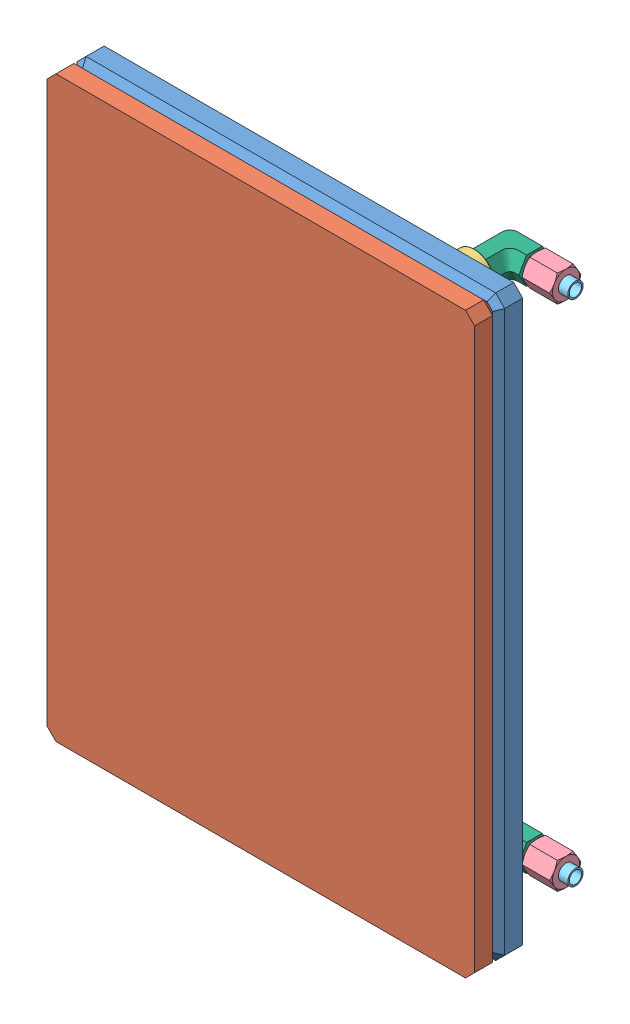
SolidWorks assembly Flanking_Shroud_Assem, configuration Default. Lengths in mm.
Overall size (225.7 304.8 64.93).
14 component instances, 7 part files, 16 mates.
Components (placement in the parent):
- Flanking_Shroud_Outside-1: Flanking_Shroud_Outside [Default] at origin size (225.42 304.8 12.7)
- Flanking_Shroud_Inside-3: Flanking_Shroud_Inside [Default] at (0 0 25.4) x (-1 0 0) z (0 0 -1) size (225.42 304.8 12.7)
- Shroud Plumbing Connection Assem-1: Shroud Plumbing Connection Assem [Default] at (74.7125 134.05 0) x (-1 0 0) z (0 0 1) size (45.23 21.34 39.53)
  - 4452K139_TYPE 316 STAINLESS STL THREADED PIPE FITTING-1: 4452K139_TYPE 316 STAINLESS STL THREADED PIPE FITTING [4452K139] at (0 0 -6.35) x (-1 0 0) z (0 0 -1) size (21.34 21.34 12.7)
  - 50715K324_37 DEGREE FLARED FITTING FOR SS TUBING-1: 50715K324_37 DEGREE FLARED FITTING FOR SS TUBING [50715K324] at (-29.6419 0 -31.226) x (0 0.999967 -0.008151) z (0 -0.008151 -0.999967) size (14.29 16.03 16.5)
  - 50715K316_TYPE 316 SS 37 DEGREE FLARED TUBE FITTING-1: 50715K316_TYPE 316 SS 37 DEGREE FLARED TUBE FITTING [50715K316] at (-29.3561 0 -31.226) x (0 0 -1) z (1 0 0) size (9.65 9.65 10.41)
  - 50715K182_37 DEGREE FLARED FITTING FOR STAINLESS STEEL TUBING-1: 50715K182_37 DEGREE FLARED FITTING FOR STAINLESS STEEL TUBING [50715K182] at (0 0 -31.226) x (1 0 0) z (0 -1 0) size (34.92 36.4 14.39)
- Shroud Plumbing Connection Assem-2: Shroud Plumbing Connection Assem [Default] at (74.7125 -134.05 0) x (-1 0 0) z (0 0 1) size (45.23 21.34 39.53)
  - 4452K139_TYPE 316 STAINLESS STL THREADED PIPE FITTING-1: 4452K139_TYPE 316 STAINLESS STL THREADED PIPE FITTING [4452K139] at (0 0 -6.35) x (-1 0 0) z (0 0 -1) size (21.34 21.34 12.7)
  - 50715K324_37 DEGREE FLARED FITTING FOR SS TUBING-1: 50715K324_37 DEGREE FLARED FITTING FOR SS TUBING [50715K324] at (-29.6419 0 -31.226) x (0 0.999967 -0.008151) z (0 -0.008151 -0.999967) size (14.29 16.03 16.5)
  - 50715K316_TYPE 316 SS 37 DEGREE FLARED TUBE FITTING-1: 50715K316_TYPE 316 SS 37 DEGREE FLARED TUBE FITTING [50715K316] at (-29.3561 0 -31.226) x (0 0 -1) z (1 0 0) size (9.65 9.65 10.41)
  - 50715K182_37 DEGREE FLARED FITTING FOR STAINLESS STEEL TUBING-1: 50715K182_37 DEGREE FLARED FITTING FOR STAINLESS STEEL TUBING [50715K182] at (0 0 -31.226) x (1 0 0) z (0 -1 0) size (34.92 36.4 14.39)
- 95931A116_18-8 SS VENTED ROUNDED HEAD SCREW-1: 95931A116_18-8 SS VENTED ROUNDED HEAD SCREW [95931A116] at (-107.7125 113.6 -2.6) x (-1 0 0) z (0 0 -1) size (7.6 7.6 8.58)
- 95931A116_18-8 SS VENTED ROUNDED HEAD SCREW-3: 95931A116_18-8 SS VENTED ROUNDED HEAD SCREW [95931A116] at (-107.7125 -113.6 -2.6) x (0.826669 -0.562689 0) z (0 0 -1) size (7.6 7.6 8.58)
Mates (geometry in assembly coordinates):
- Coincident3: coincident anti-aligned: plane of Flanking_Shroud_Outside-1 through (0 0 12.7) normal (0 0 1); plane of Flanking_Shroud_Inside-3 through (0 0 12.7) normal (0 0 -1)
- Coincident5: coincident aligned: plane of Flanking_Shroud_Outside-1 through (112.7125 -152.4 12.7) normal (1 0 0); plane of Flanking_Shroud_Inside-3 through (112.7125 -152.4 12.7) normal (1 0 0)
- Coincident14: coincident anti-aligned: plane of Flanking_Shroud_Outside-1 through (0 0 0) normal (0 0 -1); plane of Shroud Plumbing Connection Assem-1/4452K139_TYPE 316 STAINLESS STL THREADED PIPE FITTING-1 through (74.7125 134.05 0) normal (0 0 1)
- Concentric11: concentric aligned: circle of Flanking_Shroud_Outside-1; circle of 95931A116_18-8 SS VENTED ROUNDED HEAD SCREW-1
- Distance1: distance = 0.4 mm anti-aligned: plane of 95931A116_18-8 SS VENTED ROUNDED HEAD SCREW-1 through (-107.7125 109.8 -0.4) normal (0 0 1); plane of Flanking_Shroud_Outside-1 through (0 0 0) normal (0 0 -1)
- Concentric12: concentric aligned: circle of Flanking_Shroud_Outside-1; circle of 95931A116_18-8 SS VENTED ROUNDED HEAD SCREW-3
- Distance2: distance = 0.4 mm anti-aligned: plane of 95931A116_18-8 SS VENTED ROUNDED HEAD SCREW-3 through (-105.5743 -110.4587 -0.4) normal (0 0 1); plane of Flanking_Shroud_Outside-1 through (0 0 0) normal (0 0 -1)
- Coincident16: coincident aligned: plane of Flanking_Shroud_Outside-1 through (112.7125 152.4 12.7) normal (0 1 0); plane of Flanking_Shroud_Inside-3 through (-112.7125 152.4 12.7) normal (0 1 0)
- Coincident17: coincident aligned: plane of Flanking_Shroud_Outside-1 through (0 0 0) normal (0 0 1)
- Coincident18: coincident aligned: plane of Flanking_Shroud_Outside-1 through (0 0 0) normal (0 1 0)
- Coincident19: coincident aligned: plane of Flanking_Shroud_Outside-1 through (0 0 0) normal (1 0 0)
- Concentric13: concentric aligned: circle of Flanking_Shroud_Outside-1; circle of Shroud Plumbing Connection Assem-1/4452K139_TYPE 316 STAINLESS STL THREADED PIPE FITTING-1
- Parallel1: parallel aligned: plane of Shroud Plumbing Connection Assem-1/50715K182_37 DEGREE FLARED FITTING FOR STAINLESS STEEL TUBING-1 through (74.7125 134.05 -31.226) normal (0 1 0)
- Coincident20: coincident anti-aligned: plane of Flanking_Shroud_Outside-1 through (0 0 0) normal (0 0 -1); plane of Shroud Plumbing Connection Assem-2/4452K139_TYPE 316 STAINLESS STL THREADED PIPE FITTING-1 through (74.7125 -134.05 0) normal (0 0 1)
- Concentric14: concentric aligned: circle of Flanking_Shroud_Outside-1; circle of Shroud Plumbing Connection Assem-2/4452K139_TYPE 316 STAINLESS STL THREADED PIPE FITTING-1
- Parallel2: parallel anti-aligned: plane of Shroud Plumbing Connection Assem-2 through (74.7125 -134.05 0) normal (0 -1 0)
